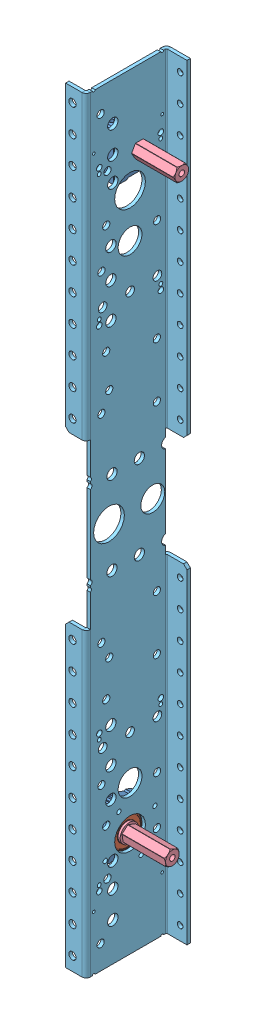
SolidWorks assembly AM14U3InnerPlate_Square_With_Weels, configuration Default. Lengths in mm.
Overall size (64.12 711.2 77.72).
11 component instances, 5 part files, 5 mates.
Components (placement in the parent):
- v2-VersaPlanetary-1stage-with-BAG-20161031-1: v2-VersaPlanetary-1stage-with-BAG-20161031 [Default] at (22.2509 113.7667 194.5314) size (64.12 44.45 42.49)
  - 217-2625-026 Rev1-1: 217-2625-026 Rev1 [Default] at (108.1713 17.6297 9.0614) x (0 -1 0) z (-1 0 0) size (44.45 42 18.13)
  - 217-2742-001 Rev4-2: 217-2742-001 Rev4 [Default] at (124.7963 17.6297 9.0614) x (1 0 0) z (0 0.20319 0.979139) size (7 28 28)
  - 217-2625-017 Rev1_9714K61-1: 217-2625-017 Rev1_9714K61 [Default] at (117.9519 17.9 9.2918) x (0 0.597426 0.801924) z (0 -0.801924 0.597426) size (28.51 4.98 30.18)
  - 217-2625-003 Rev1-1: 217-2625-003 Rev1 [Default] at (124.0439 17.6297 9.0614) x (0 -1 0) z (1 0 0) size (17 17 64.12)
- AM14U3InnerPlate_Square-1: AM14U3InnerPlate_Square [Default] at (156.7222 -562.4557 249.1392) x (0 1 0) z (0 0 1) size (711.2 38.1 77.72)
- v2-VersaPlanetary-1stage-with-BAG-20161031-2: v2-VersaPlanetary-1stage-with-BAG-20161031 [Default] at (22.2509 -394.9472 214.6842) x (1 0 0) z (0 -0.347281 -0.937761) size (64.12 44.45 42.49)
  - 217-2625-026 Rev1-1: 217-2625-026 Rev1 [Default] at (108.1713 17.6297 9.0614) x (0 -1 0) z (-1 0 0) size (44.45 42 18.13)
  - 217-2742-001 Rev4-2: 217-2742-001 Rev4 [Default] at (124.7963 17.6297 9.0614) x (1 0 0) z (0 0.20319 0.979139) size (7 28 28)
  - 217-2625-017 Rev1_9714K61-1: 217-2625-017 Rev1_9714K61 [Default] at (117.9519 17.9 9.2918) x (0 0.597426 0.801924) z (0 -0.801924 0.597426) size (28.51 4.98 30.18)
  - 217-2625-003 Rev1-1: 217-2625-003 Rev1 [Default] at (124.0439 17.6297 9.0614) x (0 -1 0) z (1 0 0) size (17 17 64.12)
Mates (geometry in assembly coordinates):
- Concentric1: concentric anti-aligned: cylinder of AM14U3InnerPlate_Square-1 through (175.7722 -385.758 203.5708) axis (-1 0 0) radius 14.2875; cylinder of ? through (158.5472 -385.758 203.5708) axis (1 0 0) radius 12.1666
- Concentric2: concentric anti-aligned: cylinder of ? through (158.5472 131.3837 203.5708) axis (1 0 0) radius 12.1666; cylinder of AM14U3InnerPlate_Square-1 through (175.7722 131.3837 203.5708) axis (-1 0 0) radius 14.2875
- Coincident1: coincident anti-aligned: plane of v2-VersaPlanetary-1stage-with-BAG-20161031-1/217-2625-026 Rev1-1 through (153.5472 153.6214 225.8178) normal (1 0 0); plane of AM14U3InnerPlate_Square-1 through (153.5472 -562.4557 179.2892) normal (-1 0 0)
- Coincident2: coincident anti-aligned: plane of AM14U3InnerPlate_Square-1 through (153.5472 -562.4557 179.2892) normal (-1 0 0); plane of v2-VersaPlanetary-1stage-with-BAG-20161031-2/217-2625-026 Rev1-1 through (153.5472 -443.1866 199.1858) normal (1 0 0)
- Concentric3: concentric aligned: circle of AM14U3InnerPlate_Square-1; cylinder of v2-VersaPlanetary-1stage-with-BAG-20161031-2/217-2742-001 Rev4-2 through (147.0472 -414.6265 212.3092) axis (-1 0 0) radius 8.75
